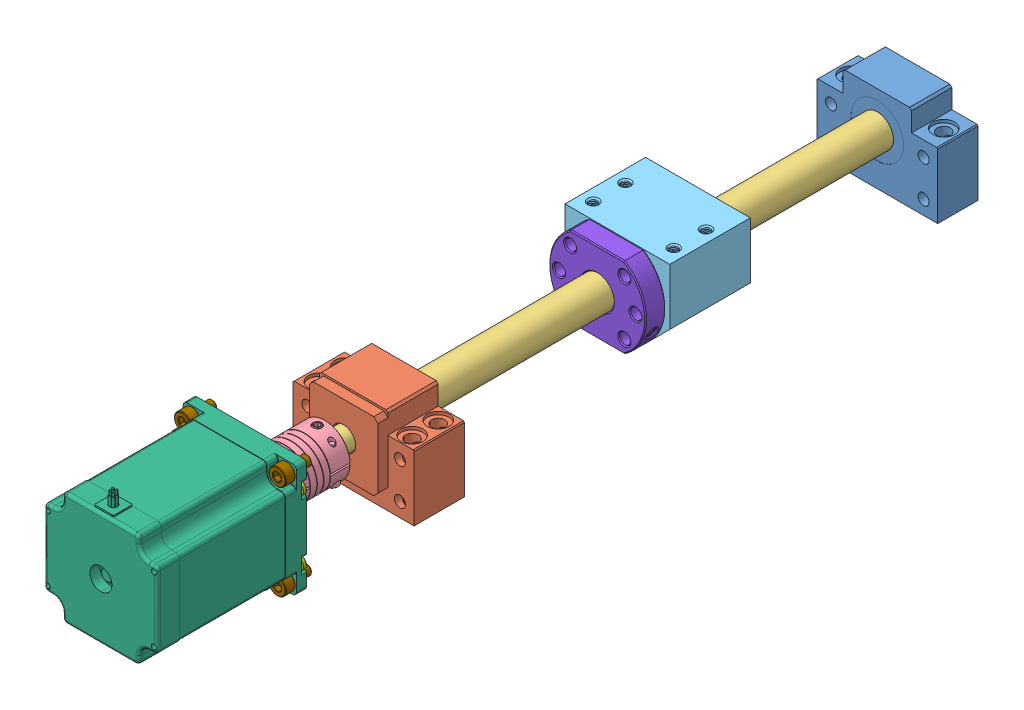
SolidWorks assembly Lead Screw Subassembly, configuration 250mm. Lengths in mm.
Overall size (60 64.12 405.45).
16 component instances, 9 part files, 30 mates.
Components (placement in the parent):
- BF12-1: BF12 [По умолчанию] at (0 69.625 -135) size (60 43 20)
- BK12-1: BK12 [По умолчанию] at (0 69.625 134.95) size (60 43 30)
- Ball Screw-1: Ball Screw [300mm] at origin size (16 16 300)
- Shaft_Coupler_6.35x12mm-1: Shaft_Coupler_6.35x12mm [По умолчанию] at (0 69.625 178.95) x (-1 0 0) z (0 -1 0) size (25.41 30 25.41)
- DSG16H-1: DSG16H [Default] at (0 89.625 4.0223) x (-1 0 0) z (0 -1 0) size (52 40 40)
- NEMA 23 - 76mm-1: NEMA 23 - 76mm [Default] at (-99.6868 69.625 260.45) x (1 0 0) z (0 1 0) size (58.2 96.5 63.21)
  - NEMA 23 - 76mm.STEP-1: NEMA 23 - 76mm.STEP [Default] at (99.6868 0 0) size (56.21 96.5 63.21)
  - pan head cross recess screw_iso_ISO 7045 - M3 x 10 - Z - 10N.STEP-1: pan head cross recess screw_iso_ISO 7045 - M3 x 10 - Z - 10N.STEP [Default] at (125.9868 73.9 -16.15) x (0 -1 0) z (0 0 1) size (12.36 5.6 5.6)
  - pan head cross recess screw_iso_ISO 7045 - M3 x 10 - Z - 10N.STEP-2: pan head cross recess screw_iso_ISO 7045 - M3 x 10 - Z - 10N.STEP [Default] at (125.9868 73.9 16.15) x (0 -1 0) z (0 0 1) size (12.36 5.6 5.6)
  - pan head cross recess screw_iso_ISO 7045 - M3 x 10 - Z - 10N.STEP-3: pan head cross recess screw_iso_ISO 7045 - M3 x 10 - Z - 10N.STEP [Default] at (73.3868 73.9 16.15) x (0 -1 0) z (0 0 1) size (12.36 5.6 5.6)
  - pan head cross recess screw_iso_ISO 7045 - M3 x 10 - Z - 10N.STEP-4: pan head cross recess screw_iso_ISO 7045 - M3 x 10 - Z - 10N.STEP [Default] at (73.3868 73.9 -16.15) x (0 -1 0) z (0 0 1) size (12.36 5.6 5.6)
- RM1605-1: RM1605 [Default] at (0 69.625 14.0223) x (1 0 0) z (0 1 0) size (48 42 40)
- 90128A234_Zinc-Plated Alloy Steel Socket Head Screw-1: 90128A234_Zinc-Plated Alloy Steel Socket Head Screw [90128A234] at (23.5 93.125 188.95) size (8.5 8.5 15.23)
- 90128A234_Zinc-Plated Alloy Steel Socket Head Screw-2: 90128A234_Zinc-Plated Alloy Steel Socket Head Screw [90128A234] at (23.5 46.125 188.95) x (0.987351 0.158553 0) z (0 0 1) size (8.5 8.5 15.23)
- 90128A234_Zinc-Plated Alloy Steel Socket Head Screw-3: 90128A234_Zinc-Plated Alloy Steel Socket Head Screw [90128A234] at (-23.5 93.125 188.95) x (0.959125 0.282984 0) z (0 0 1) size (8.5 8.5 15.23)
- 90128A234_Zinc-Plated Alloy Steel Socket Head Screw-4: 90128A234_Zinc-Plated Alloy Steel Socket Head Screw [90128A234] at (-23.5 46.125 188.95) x (0.928571 0.371154 0) z (0 0 1) size (8.5 8.5 15.23)
Mates (geometry in assembly coordinates):
- Coincident5: coincident aligned: plane of BF12-1 through (0 69.625 -135) normal (1 0 0)
- Coincident6: coincident aligned: plane of BK12-1 through (0 69.625 134.95) normal (1 0 0)
- Concentric1: concentric aligned: cylinder of BF12-1 through (0 69.625 -133.05) axis (0 0 1) radius 5; cylinder of Ball Screw-1 through (0 69.625 163.95) axis (0 0 1) radius 5
- Coincident7: coincident anti-aligned: plane of BK12-1 through (0 106.625 109.95) normal (0 0 -1); plane of Ball Screw-1 through (0 63.625 109.95) normal (0 0 1)
- Coincident8: coincident anti-aligned: plane of BF12-1 through (0 69.625 -125.05) normal (0 0 1); plane of Ball Screw-1 through (0 61.625 -125.05) normal (0 0 -1)
- Concentric2: concentric anti-aligned: cylinder of Ball Screw-1 through (0 69.625 163.95) axis (0 0 1) radius 5; cylinder of Shaft_Coupler_6.35x12mm-1 through (0 69.625 163.95) axis (0 0 -1) radius 5
- Coincident9: coincident anti-aligned: plane of Ball Screw-1 through (0 64.625 148.95) normal (0 0 1); plane of Shaft_Coupler_6.35x12mm-1 through (0 69.625 148.95) normal (0 0 -1)
- Concentric3: concentric anti-aligned: cylinder of Ball Screw-1 through (0 69.625 163.95) axis (0 0 1) radius 8; cylinder of DSG16H-1 through (0 69.625 4.0223) axis (0 0 -1) radius 14
- Concentric4: concentric aligned: cylinder of Shaft_Coupler_6.35x12mm-1 through (0 69.625 163.95) axis (0 0 1) radius 3.175; cylinder of NEMA 23 - 76mm-1/NEMA 23 - 76mm.STEP-1 through (0 69.625 134.4697) axis (0 0 1) radius 3.175
- Coincident11: coincident anti-aligned: plane of Ball Screw-1 through (0 69.625 163.95) normal (0 0 1); plane of NEMA 23 - 76mm-1/NEMA 23 - 76mm.STEP-1 through (0 69.625 163.95) normal (0 0 -1)
- Parallel1: parallel aligned: plane of NEMA 23 - 76mm-1/NEMA 23 - 76mm.STEP-1 through (17 97.475 185.95) normal (0 1 0)
- Concentric5: concentric aligned: cylinder of BK12-1 through (0 69.625 109.95) axis (0 0 1) radius 6; cylinder of Ball Screw-1 through (0 69.625 163.95) axis (0 0 1) radius 8
- Coincident13: coincident aligned: plane of Ball Screw-1 through (0 0 0) normal (0 0 1)
- Coincident14: coincident aligned: plane of Ball Screw-1 through (0 0 0) normal (0 1 0)
- Coincident15: coincident aligned: plane of Ball Screw-1 through (0 0 0) normal (1 0 0)
- Parallel2: parallel anti-aligned: plane of Shaft_Coupler_6.35x12mm-1 through (0 69.625 178.95) normal (0 -1 0)
- Parallel3: parallel aligned: plane of DSG16H-1 through (-26 89.625 4.0223) normal (0 1 0)
- Concentric6: concentric aligned: cylinder of DSG16H-1 through (0 69.625 4.0223) axis (0 0 -1) radius 14; cylinder of RM1605-1 through (0 69.625 14.0223) axis (0 0 -1) radius 14
- Parallel4: parallel aligned: plane of DSG16H-1 through (-26 89.625 4.0223) normal (0 1 0); plane of RM1605-1 through (-13.2665 89.625 14.0223) normal (0 1 0)
- Coincident16: coincident anti-aligned: plane of DSG16H-1 through (0 69.625 4.0223) normal (0 0 1); plane of RM1605-1 through (0 69.625 4.0223) normal (0 0 -1)
- LimitDistance1: limit distance = 95.9277 mm anti-aligned: plane of RM1605-1 through (0 69.625 14.0223) normal (0 0 1); plane of BK12-1 through (0 106.625 109.95) normal (0 0 -1)
- LimitDistance2: limit distance = 89.0223 mm anti-aligned: plane of DSG16H-1 through (0 69.625 -35.9777) normal (0 0 -1); plane of BF12-1 through (30 44.625 -125) normal (0 0 1)
- Concentric7: concentric anti-aligned: cylinder of NEMA 23 - 76mm-1/NEMA 23 - 76mm.STEP-1 through (23.5 93.125 191.45) axis (0 0 -1) radius 2.5; cylinder of 90128A234_Zinc-Plated Alloy Steel Socket Head Screw-1 through (23.5 93.125 196.45) axis (0 0 1) radius 4.25
- Coincident17: coincident anti-aligned: plane of NEMA 23 - 76mm-1/NEMA 23 - 76mm.STEP-1 through (26.1 95.725 191.45) normal (0 0 1); plane of 90128A234_Zinc-Plated Alloy Steel Socket Head Screw-1 through (23.5 95.625 191.45) normal (0 0 -1)
- Coincident18: coincident anti-aligned: plane of NEMA 23 - 76mm-1/NEMA 23 - 76mm.STEP-1 through (26.1 95.725 191.45) normal (0 0 1); plane of 90128A234_Zinc-Plated Alloy Steel Socket Head Screw-2 through (23.1036 48.5934 191.45) normal (0 0 -1)
- Concentric8: concentric anti-aligned: cylinder of NEMA 23 - 76mm-1/NEMA 23 - 76mm.STEP-1 through (23.5 46.125 191.45) axis (0 0 -1) radius 2.5; cylinder of 90128A234_Zinc-Plated Alloy Steel Socket Head Screw-2 through (23.5 46.125 196.45) axis (0 0 1) radius 4.25
- Coincident19: coincident anti-aligned: plane of NEMA 23 - 76mm-1/NEMA 23 - 76mm.STEP-1 through (26.1 95.725 191.45) normal (0 0 1); plane of 90128A234_Zinc-Plated Alloy Steel Socket Head Screw-3 through (-24.2075 95.5228 191.45) normal (0 0 -1)
- Concentric9: concentric anti-aligned: cylinder of NEMA 23 - 76mm-1/NEMA 23 - 76mm.STEP-1 through (-23.5 93.125 191.45) axis (0 0 -1) radius 2.5; cylinder of 90128A234_Zinc-Plated Alloy Steel Socket Head Screw-3 through (-23.5 93.125 196.45) axis (0 0 1) radius 4.25
- Coincident20: coincident anti-aligned: plane of NEMA 23 - 76mm-1/NEMA 23 - 76mm.STEP-1 through (26.1 95.725 191.45) normal (0 0 1); plane of 90128A234_Zinc-Plated Alloy Steel Socket Head Screw-4 through (-24.4279 48.4464 191.45) normal (0 0 -1)
- Concentric10: concentric anti-aligned: cylinder of NEMA 23 - 76mm-1/NEMA 23 - 76mm.STEP-1 through (-23.5 46.125 191.45) axis (0 0 -1) radius 2.5; cylinder of 90128A234_Zinc-Plated Alloy Steel Socket Head Screw-4 through (-23.5 46.125 196.45) axis (0 0 1) radius 4.25
